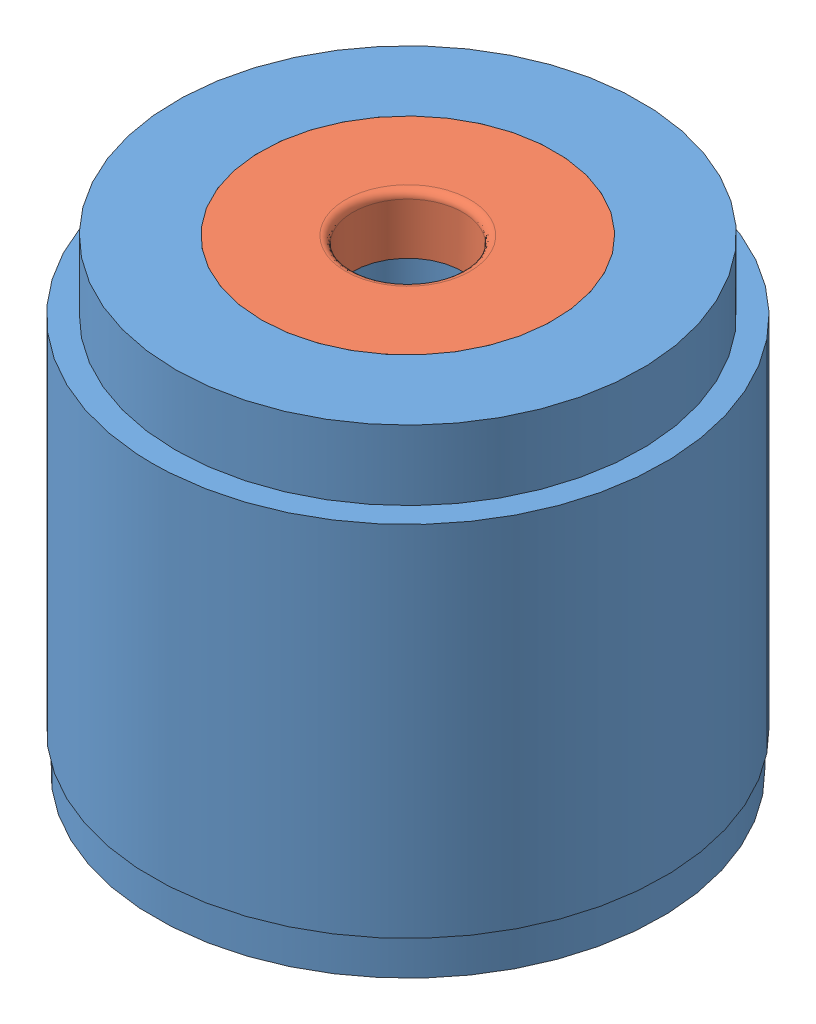
SolidWorks assembly Cup, configuration Default. Lengths in mm.
Overall size (69.82 63.5 69.82).
2 component instances, 2 part files, 1 mates.
Components (placement in the parent):
- Die Body-1: Die Body [Default] at (0 -31.75 0) size (69.82 63.5 69.82)
- Die Insert-1: Die Insert [Default] at (0 23.75 0) size (40 8 40)
Mates (geometry in assembly coordinates):
- Coincident1: coincident anti-aligned: plane of Die Body-1 through (0 23.75 0) normal (0 1 0); plane of Die Insert-1 through (0 23.75 0) normal (0 -1 0)
